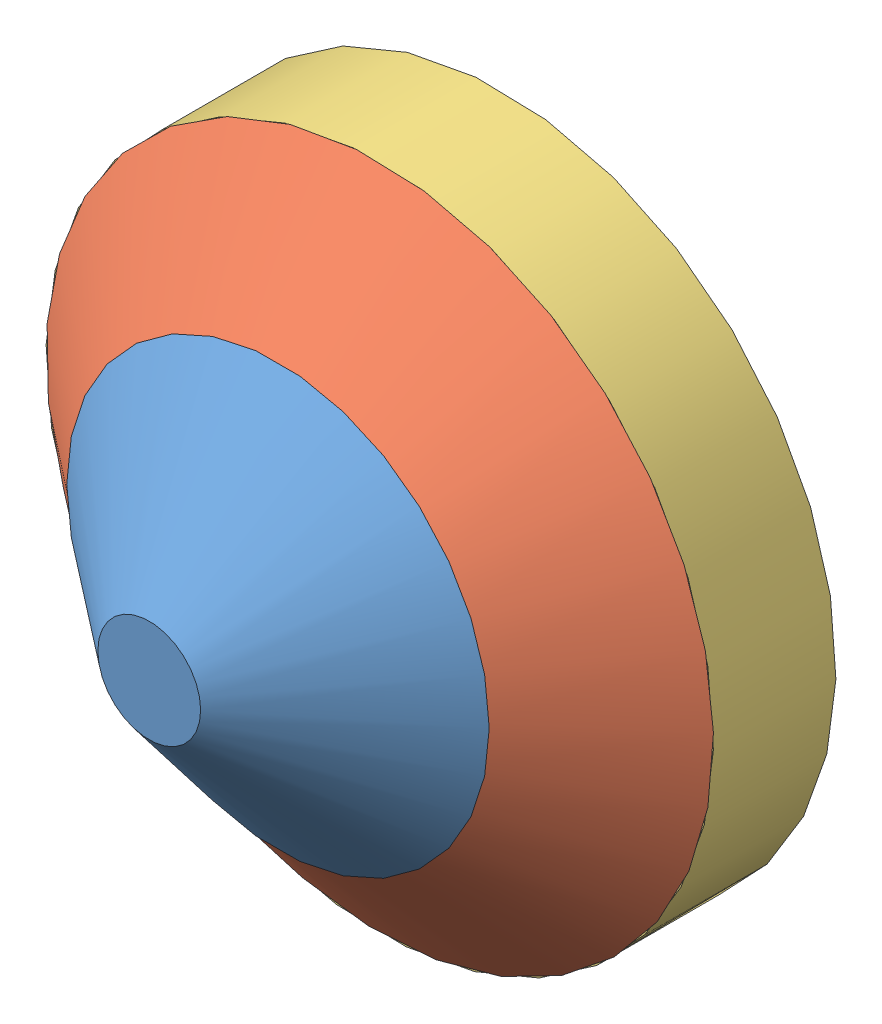
SolidWorks assembly ETA_1, configuration Default. Lengths in mm.
Overall size (348.91 348.91 141.2).
4 component instances, 4 part files, 6 mates.
Components (placement in the parent):
- Ta-1: Ta [Default] at (16.2169 49.8318 154.765) size (165.94 165.94 51.5)
- Bi_1-1: Bi_1 [Default] at (16.2169 49.8318 114.065) x (-0.992806 -0.119734 0) z (0 0 1) size (267 267 40.7)
- Bi_2_m-1: Bi_2_m [Default] at (16.2169 49.8318 114.065) x (-0.923728 -0.383049 0) z (0 0 -1) size (267 267 49)
- Si_1-1: Si_1 [Default] at (16.2169 49.8318 69.765) x (-0.923728 -0.383049 0) z (0 0 -1) size (174 174 4.7)
Mates (geometry in assembly coordinates):
- Coincident3: coincident anti-aligned: plane of Ta-1 through (16.2169 49.8318 154.765) normal (0 0 -1); plane of Bi_1-1 through (16.2169 49.8318 154.765) normal (0 0 1)
- Concentric1: concentric aligned: circle of Ta-1; circle of Bi_1-1
- Coincident6: coincident anti-aligned: plane of Bi_2_m-1 through (16.2169 49.8318 69.765) normal (0 0 -1); plane of Si_1-1 through (16.2169 49.8318 69.765) normal (0 0 1)
- Coincident7: coincident aligned: circle of Bi_2_m-1; circle of Si_1-1
- Coincident9: coincident anti-aligned: plane of Bi_1-1 through (16.2169 49.8318 114.065) normal (0 0 -1); plane of Bi_2_m-1 through (16.2169 49.8318 114.065) normal (0 0 1)
- Coincident12: coincident anti-aligned: circle of Bi_1-1; circle of Bi_2_m-1
